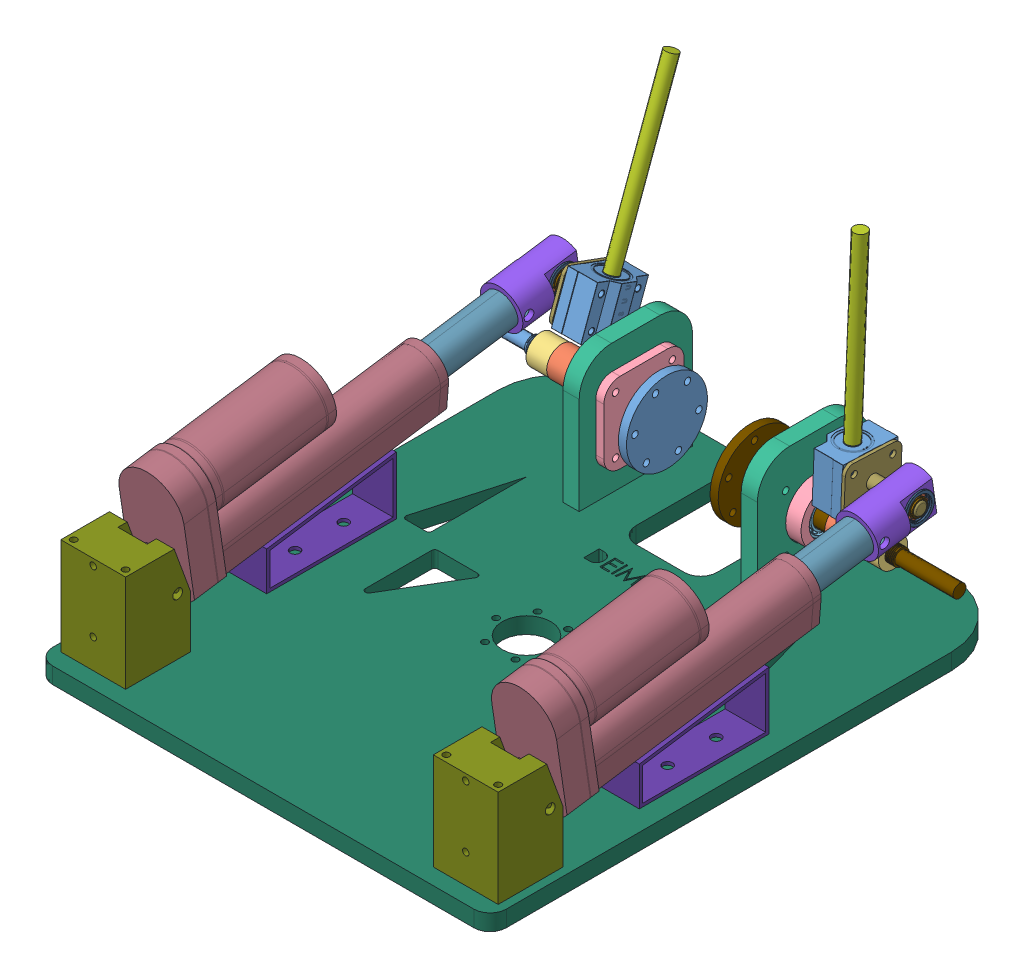
SolidWorks assembly Arm_base_2025_Final, configuration Default. Lengths in mm.
Overall size (299.6 226.1 337.68).
87 component instances, 19 part files, 69 mates.
Components (placement in the parent):
- V8_shaftURC 2024_V4-1: V8_shaftURC 2024_V4 [Default] at (197.7714 146.5943 146.238) x (1 0 0) z (0 -0.634045 -0.773296) size (119 50 50)
- linnear rod coupler-1: linnear rod coupler [Default] at (207.7714 137.6403 153.5796) x (0 -0.344758 -0.938692) z (-1 0 0) size (18.5 18.5 20.01)
- lock_nut_for coupler-1: lock_nut_for coupler [Default] at (187.7714 137.6403 153.5796) x (0 0.998189 -0.060159) z (-1 0 0) size (18 18 13)
- base bearing assambly-1: base bearing assambly [Default] at (252.6957 114.573 131.7936) x (0 0 1) z (-1 0 0) size (49.5 49.5 24)
  - base shaft bearing housing-1: base shaft bearing housing [Default] at (21.786 23.0673 38.1242) size (49.5 49.5 24)
  - 61802  15x24x5mm-1: 61802  15x24x5mm [Default] at (21.786 23.0673 36.1242) x (0 0 -1) z (1 0 0) size (5 24 24)
  - 61802  15x24x5mm-2: 61802  15x24x5mm [Default] at (21.786 23.0673 21.1242) x (0 0 -1) z (1 0 0) size (5 24 24)
- V8_bearing holder holderURC 2024_V4-1: V8_bearing holder holderURC 2024_V4 [Default] at (233.5714 177.6403 118.5796) x (0 0 1) z (-1 0 0) size (70 110 10)
- linear guid rod-1: linear guid rod [Default] at (201.7714 143.2724 151.511) x (0.999217 0.013638 0.037132) z (-0.039557 0.344488 0.937957) size (8 150 8)
- Connector to Linear bearing-1: Connector to Linear bearing [Default] at (150.0852 181.1033 174.7312) x (1 0 0) z (0 0.146923 -0.989148) size (26 26 42.97)
  - V8_connectorURC 2024_V4-1: V8_connectorURC 2024_V4 [Default] at (18.4863 3.099 40.9035) size (26 26 40)
  - V8_F688ZZ_assemblyURC 2024_V4-1: V8_F688ZZ_assemblyURC 2024_V4 [Default] at (27.6778 16.099 30.9035) x (0 1 0) z (0 0 1) size (20.89 5 20.89)
    - V8_F688ZZ_shaftURC 2024_V4-1: V8_F688ZZ_shaftURC 2024_V4 [Default] at origin size (10.7 5 10.7)
    - V8_F688ZZ_HousingURC 2024_V4-1: V8_F688ZZ_HousingURC 2024_V4 [Default] x (0.984312 0 0.176438) z (-0.176438 0 0.984312) size (18 5 18)
    - V8_F688ZZ_BallURC 2024_V4-1: V8_F688ZZ_BallURC 2024_V4 [Default] at (5.5752 2.5 -2.1489) x (0.959238 0.232099 0.161224) z (-0.142462 -0.095558 0.985177) size (2 2 2)
    - V8_F688ZZ_BallURC 2024_V4-20: V8_F688ZZ_BallURC 2024_V4 [Default] at (3.2474 2.5 -5.0155) x (0.870805 0.232099 -0.433393) z (0.463818 -0.095558 0.880762) size (2 2 2)
    - V8_F688ZZ_BallURC 2024_V4-21: V8_F688ZZ_BallURC 2024_V4 [Default] at (-0.3209 2.5 -5.9664) x (0.449753 0.232099 -0.862469) z (0.892936 -0.095558 0.439926) size (2 2 2)
    - V8_F688ZZ_BallURC 2024_V4-22: V8_F688ZZ_BallURC 2024_V4 [Default] at (-3.7665 2.5 -4.6383) x (-0.143088 0.232099 -0.96211) z (0.980982 -0.095558 -0.168947) size (2 2 2)
    - V8_F688ZZ_BallURC 2024_V4-23: V8_F688ZZ_BallURC 2024_V4 [Default] at (-5.7735 2.5 -1.5385) x (-0.681275 0.232099 -0.694258) z (0.694326 -0.095558 -0.713288) size (2 2 2)
    - V8_F688ZZ_BallURC 2024_V4-24: V8_F688ZZ_BallURC 2024_V4 [Default] at (-5.5752 2.5 2.1489) x (-0.959238 0.232099 -0.161224) z (0.142462 -0.095558 -0.985177) size (2 2 2)
    - V8_F688ZZ_BallURC 2024_V4-25: V8_F688ZZ_BallURC 2024_V4 [Default] at (-3.2474 2.5 5.0155) x (-0.870805 0.232099 0.433393) z (-0.463818 -0.095558 -0.880762) size (2 2 2)
    - V8_F688ZZ_BallURC 2024_V4-26: V8_F688ZZ_BallURC 2024_V4 [Default] at (0.3209 2.5 5.9664) x (-0.449753 0.232099 0.862469) z (-0.892936 -0.095558 -0.439926) size (2 2 2)
    - V8_F688ZZ_BallURC 2024_V4-27: V8_F688ZZ_BallURC 2024_V4 [Default] at (3.7665 2.5 4.6383) x (0.143088 0.232099 0.96211) z (-0.980982 -0.095558 0.168947) size (2 2 2)
    - V8_F688ZZ_BallURC 2024_V4-28: V8_F688ZZ_BallURC 2024_V4 [Default] at (5.7735 2.5 1.5385) x (0.681275 0.232099 0.694258) z (-0.694326 -0.095558 0.713288) size (2 2 2)
  - V8_F688ZZ_assemblyURC 2024_V4-2: V8_F688ZZ_assemblyURC 2024_V4 [Default] at (9.2948 16.099 30.9035) x (0 -0.381849 0.924225) z (0 0.924225 0.381849) size (20.89 5 20.89)
    - V8_F688ZZ_shaftURC 2024_V4-1: V8_F688ZZ_shaftURC 2024_V4 [Default] at origin size (10.7 5 10.7)
    - V8_F688ZZ_HousingURC 2024_V4-1: V8_F688ZZ_HousingURC 2024_V4 [Default] x (0.984312 0 0.176438) z (-0.176438 0 0.984312) size (18 5 18)
    - V8_F688ZZ_BallURC 2024_V4-1: V8_F688ZZ_BallURC 2024_V4 [Default] at (5.5752 2.5 -2.1489) x (0.959238 0.232099 0.161224) z (-0.142462 -0.095558 0.985177) size (2 2 2)
    - V8_F688ZZ_BallURC 2024_V4-20: V8_F688ZZ_BallURC 2024_V4 [Default] at (3.2474 2.5 -5.0155) x (0.870805 0.232099 -0.433393) z (0.463818 -0.095558 0.880762) size (2 2 2)
    - V8_F688ZZ_BallURC 2024_V4-21: V8_F688ZZ_BallURC 2024_V4 [Default] at (-0.3209 2.5 -5.9664) x (0.449753 0.232099 -0.862469) z (0.892936 -0.095558 0.439926) size (2 2 2)
    - V8_F688ZZ_BallURC 2024_V4-22: V8_F688ZZ_BallURC 2024_V4 [Default] at (-3.7665 2.5 -4.6383) x (-0.143088 0.232099 -0.96211) z (0.980982 -0.095558 -0.168947) size (2 2 2)
    - V8_F688ZZ_BallURC 2024_V4-23: V8_F688ZZ_BallURC 2024_V4 [Default] at (-5.7735 2.5 -1.5385) x (-0.681275 0.232099 -0.694258) z (0.694326 -0.095558 -0.713288) size (2 2 2)
    - V8_F688ZZ_BallURC 2024_V4-24: V8_F688ZZ_BallURC 2024_V4 [Default] at (-5.5752 2.5 2.1489) x (-0.959238 0.232099 -0.161224) z (0.142462 -0.095558 -0.985177) size (2 2 2)
    - V8_F688ZZ_BallURC 2024_V4-25: V8_F688ZZ_BallURC 2024_V4 [Default] at (-3.2474 2.5 5.0155) x (-0.870805 0.232099 0.433393) z (-0.463818 -0.095558 -0.880762) size (2 2 2)
    - V8_F688ZZ_BallURC 2024_V4-26: V8_F688ZZ_BallURC 2024_V4 [Default] at (0.3209 2.5 5.9664) x (-0.449753 0.232099 0.862469) z (-0.892936 -0.095558 -0.439926) size (2 2 2)
    - V8_F688ZZ_BallURC 2024_V4-27: V8_F688ZZ_BallURC 2024_V4 [Default] at (3.7665 2.5 4.6383) x (0.143088 0.232099 0.96211) z (-0.980982 -0.095558 0.168947) size (2 2 2)
    - V8_F688ZZ_BallURC 2024_V4-28: V8_F688ZZ_BallURC 2024_V4 [Default] at (5.7735 2.5 1.5385) x (0.681275 0.232099 0.694258) z (-0.694326 -0.095558 0.713288) size (2 2 2)
- V8_bearing and cam connection_for_v4URC 2024_V4-1: V8_bearing and cam connection_for_v4URC 2024_V4 [Default] at (188.5714 161.6723 163.3962) x (0 0.938692 -0.344758) z (1 0 0) size (30 35 32)
- V8_LA_Body_V4-1: V8_LA_Body_V4 [Default] at (168.5714 140.8866 383.557) x (0 -0.989148 -0.146923) z (-1 0 0) size (74 184 40)
- V8_LA_RodURC 2024_V4-1: V8_LA_RodURC 2024_V4 [Default] at (168.5714 166.9279 160.5915) x (1 0 0) z (0 -0.989148 -0.146923) size (20 121 20)
- V8_base plate for LAURC 2024_V4-1: V8_base plate for LAURC 2024_V4 [Default] at (283.5714 87.6403 412.2334) x (0 0 -1) z (0 1 0) size (325 280 10)
- LA_back holder-1: LA_back holder [Default] at (168.5714 157.6403 403.5796) x (-1 0 0) z (0 0 -1) size (40 60 40)
- LA_triangular holder_30mm-1: LA_triangular holder_30mm [Default] at (181.0714 97.6403 248.9692) x (0 0 1) z (-1 0 0) size (80 35.85 25)
- Connector to Linear bearing-2: Connector to Linear bearing [Default] at (380.0852 179.5504 185.186) x (1 0 0) z (0 0.146923 -0.989148) size (26 26 42.97)
  - V8_connectorURC 2024_V4-1: V8_connectorURC 2024_V4 [Default] at (18.4863 3.099 40.9035) size (26 26 40)
  - V8_F688ZZ_assemblyURC 2024_V4-1: V8_F688ZZ_assemblyURC 2024_V4 [Default] at (27.6778 16.099 30.9035) x (0 1 0) z (0 0 1) size (20.89 5 20.89)
    - V8_F688ZZ_shaftURC 2024_V4-1: V8_F688ZZ_shaftURC 2024_V4 [Default] at origin size (10.7 5 10.7)
    - V8_F688ZZ_HousingURC 2024_V4-1: V8_F688ZZ_HousingURC 2024_V4 [Default] x (0.984312 0 0.176438) z (-0.176438 0 0.984312) size (18 5 18)
    - V8_F688ZZ_BallURC 2024_V4-1: V8_F688ZZ_BallURC 2024_V4 [Default] at (5.5752 2.5 -2.1489) x (0.959238 0.232099 0.161224) z (-0.142462 -0.095558 0.985177) size (2 2 2)
    - V8_F688ZZ_BallURC 2024_V4-20: V8_F688ZZ_BallURC 2024_V4 [Default] at (3.2474 2.5 -5.0155) x (0.870805 0.232099 -0.433393) z (0.463818 -0.095558 0.880762) size (2 2 2)
    - V8_F688ZZ_BallURC 2024_V4-21: V8_F688ZZ_BallURC 2024_V4 [Default] at (-0.3209 2.5 -5.9664) x (0.449753 0.232099 -0.862469) z (0.892936 -0.095558 0.439926) size (2 2 2)
    - V8_F688ZZ_BallURC 2024_V4-22: V8_F688ZZ_BallURC 2024_V4 [Default] at (-3.7665 2.5 -4.6383) x (-0.143088 0.232099 -0.96211) z (0.980982 -0.095558 -0.168947) size (2 2 2)
    - V8_F688ZZ_BallURC 2024_V4-23: V8_F688ZZ_BallURC 2024_V4 [Default] at (-5.7735 2.5 -1.5385) x (-0.681275 0.232099 -0.694258) z (0.694326 -0.095558 -0.713288) size (2 2 2)
    - V8_F688ZZ_BallURC 2024_V4-24: V8_F688ZZ_BallURC 2024_V4 [Default] at (-5.5752 2.5 2.1489) x (-0.959238 0.232099 -0.161224) z (0.142462 -0.095558 -0.985177) size (2 2 2)
    - V8_F688ZZ_BallURC 2024_V4-25: V8_F688ZZ_BallURC 2024_V4 [Default] at (-3.2474 2.5 5.0155) x (-0.870805 0.232099 0.433393) z (-0.463818 -0.095558 -0.880762) size (2 2 2)
    - V8_F688ZZ_BallURC 2024_V4-26: V8_F688ZZ_BallURC 2024_V4 [Default] at (0.3209 2.5 5.9664) x (-0.449753 0.232099 0.862469) z (-0.892936 -0.095558 -0.439926) size (2 2 2)
    - V8_F688ZZ_BallURC 2024_V4-27: V8_F688ZZ_BallURC 2024_V4 [Default] at (3.7665 2.5 4.6383) x (0.143088 0.232099 0.96211) z (-0.980982 -0.095558 0.168947) size (2 2 2)
    - V8_F688ZZ_BallURC 2024_V4-28: V8_F688ZZ_BallURC 2024_V4 [Default] at (5.7735 2.5 1.5385) x (0.681275 0.232099 0.694258) z (-0.694326 -0.095558 0.713288) size (2 2 2)
  - V8_F688ZZ_assemblyURC 2024_V4-2: V8_F688ZZ_assemblyURC 2024_V4 [Default] at (9.2948 16.099 30.9035) x (0 -0.381849 0.924225) z (0 0.924225 0.381849) size (20.89 5 20.89)
    - V8_F688ZZ_shaftURC 2024_V4-1: V8_F688ZZ_shaftURC 2024_V4 [Default] at origin size (10.7 5 10.7)
    - V8_F688ZZ_HousingURC 2024_V4-1: V8_F688ZZ_HousingURC 2024_V4 [Default] x (0.984312 0 0.176438) z (-0.176438 0 0.984312) size (18 5 18)
    - V8_F688ZZ_BallURC 2024_V4-1: V8_F688ZZ_BallURC 2024_V4 [Default] at (5.5752 2.5 -2.1489) x (0.959238 0.232099 0.161224) z (-0.142462 -0.095558 0.985177) size (2 2 2)
    - V8_F688ZZ_BallURC 2024_V4-20: V8_F688ZZ_BallURC 2024_V4 [Default] at (3.2474 2.5 -5.0155) x (0.870805 0.232099 -0.433393) z (0.463818 -0.095558 0.880762) size (2 2 2)
    - V8_F688ZZ_BallURC 2024_V4-21: V8_F688ZZ_BallURC 2024_V4 [Default] at (-0.3209 2.5 -5.9664) x (0.449753 0.232099 -0.862469) z (0.892936 -0.095558 0.439926) size (2 2 2)
    - V8_F688ZZ_BallURC 2024_V4-22: V8_F688ZZ_BallURC 2024_V4 [Default] at (-3.7665 2.5 -4.6383) x (-0.143088 0.232099 -0.96211) z (0.980982 -0.095558 -0.168947) size (2 2 2)
    - V8_F688ZZ_BallURC 2024_V4-23: V8_F688ZZ_BallURC 2024_V4 [Default] at (-5.7735 2.5 -1.5385) x (-0.681275 0.232099 -0.694258) z (0.694326 -0.095558 -0.713288) size (2 2 2)
    - V8_F688ZZ_BallURC 2024_V4-24: V8_F688ZZ_BallURC 2024_V4 [Default] at (-5.5752 2.5 2.1489) x (-0.959238 0.232099 -0.161224) z (0.142462 -0.095558 -0.985177) size (2 2 2)
    - V8_F688ZZ_BallURC 2024_V4-25: V8_F688ZZ_BallURC 2024_V4 [Default] at (-3.2474 2.5 5.0155) x (-0.870805 0.232099 0.433393) z (-0.463818 -0.095558 -0.880762) size (2 2 2)
    - V8_F688ZZ_BallURC 2024_V4-26: V8_F688ZZ_BallURC 2024_V4 [Default] at (0.3209 2.5 5.9664) x (-0.449753 0.232099 0.862469) z (-0.892936 -0.095558 -0.439926) size (2 2 2)
    - V8_F688ZZ_BallURC 2024_V4-27: V8_F688ZZ_BallURC 2024_V4 [Default] at (3.7665 2.5 4.6383) x (0.143088 0.232099 0.96211) z (-0.980982 -0.095558 0.168947) size (2 2 2)
    - V8_F688ZZ_BallURC 2024_V4-28: V8_F688ZZ_BallURC 2024_V4 [Default] at (5.7735 2.5 1.5385) x (0.681275 0.232099 0.694258) z (-0.694326 -0.095558 0.713288) size (2 2 2)
- LA_back holder-2: LA_back holder [Default] at (398.5714 157.6403 403.5796) x (-1 0 0) z (0 0 -1) size (40 60 40)
- V8_bearing and cam connection_for_v4URC 2024_V4-2: V8_bearing and cam connection_for_v4URC 2024_V4 [Default] at (378.5714 183.9124 169.0846) x (0 -0.999056 0.04343) z (-1 0 0) size (30 35 32)
- V8_LA_RodURC 2024_V4-2: V8_LA_RodURC 2024_V4 [Default] at (398.5714 165.375 171.0464) x (1 0 0) z (0 -0.989148 -0.146923) size (20 121 20)
- linnear rod coupler-2: linnear rod coupler [Default] at (359.3714 137.6403 153.5796) x (0 0.04343 0.999056) z (1 0 0) size (18.5 18.5 20.01)
- lock_nut_for coupler-2: lock_nut_for coupler [Default] at (379.3714 137.6403 153.5796) x (0 -0.658716 -0.752392) z (1 0 0) size (18 18 13)
- linear guid rod-2: linear guid rod [Default] at (365.3714 143.6346 153.319) x (-0.587704 0.035138 0.808312) z (-0.809076 -0.025524 -0.58715) size (8 150 8)
- base bearing assambly-2: base bearing assambly [Default] at (314.4472 114.573 175.3656) x (0 0 -1) z (1 0 0) size (49.5 49.5 24)
  - base shaft bearing housing-1: base shaft bearing housing [Default] at (21.786 23.0673 38.1242) size (49.5 49.5 24)
  - 61802  15x24x5mm-1: 61802  15x24x5mm [Default] at (21.786 23.0673 36.1242) x (0 0 -1) z (1 0 0) size (5 24 24)
  - 61802  15x24x5mm-2: 61802  15x24x5mm [Default] at (21.786 23.0673 21.1242) x (0 0 -1) z (1 0 0) size (5 24 24)
- base_shaft_link2_V4-1: base_shaft_link2_V4 [Default] at (359.3714 130.6412 162.8038) x (-1 0 0) z (0 -0.796635 -0.604461) size (129 50 50)
- LA_triangular holder_30mm-2: LA_triangular holder_30mm [Default] at (411.0714 97.6403 248.9692) x (0 0 1) z (-1 0 0) size (80 35.85 25)
- V8_bearing holder holderURC 2024_V4-2: V8_bearing holder holderURC 2024_V4 [Default] at (333.5714 177.6403 188.5796) x (0 0 -1) z (1 0 0) size (70 110 10)
- V8_LA_Body_V4-2: V8_LA_Body_V4 [Default] at (398.5714 140.8866 383.557) x (0 -0.989148 -0.146923) z (-1 0 0) size (74 184 40)
- linear bearing robotic arm-1: linear bearing robotic arm [Default] at (199.3393 155.6391 146.9691) x (0 -0.344758 -0.938692) z (1 0 0) size (34 30.1 22.2)
- linear bearing robotic arm-2: linear bearing robotic arm [Default] at (367.8035 183.1523 151.6012) x (0 -0.04343 -0.999056) z (-1 0 0) size (34 30.1 22.2)
Mates (geometry in assembly coordinates):
- Coincident12: coincident anti-aligned: plane of V8_base plate for LAURC 2024_V4-1 through (283.5714 97.6403 412.2334) normal (0 1 0); plane of LA_back holder-1 through (168.5714 97.6403 403.5796) normal (0 -1 0)
- Concentric4: concentric anti-aligned: cylinder of Connector to Linear bearing-1/V8_F688ZZ_assemblyURC 2024_V4-2/V8_F688ZZ_shaftURC 2024_V4-1 through (164.3799 169.7194 141.7977) axis (-1 0 0) radius 4; cylinder of V8_bearing and cam connection_for_v4URC 2024_V4-1 through (158.5714 169.7194 141.7977) axis (1 0 0) radius 4
- Distance6: distance = 20 mm: cylinder of Connector to Linear bearing-1/V8_connectorURC 2024_V4-1 through (168.5714 167.5156 156.635) axis (0 -0.146923 0.989148) radius 13; plane of V8_bearing and cam connection_for_v4URC 2024_V4-1 through (188.5714 161.6723 163.3962) normal (-1 0 0)
- Concentric9: concentric anti-aligned: cylinder of Connector to Linear bearing-1/V8_connectorURC 2024_V4-1 through (168.5714 167.5156 156.635) axis (0 -0.146923 0.989148) radius 10; cylinder of V8_LA_RodURC 2024_V4-1 through (168.5714 149.1502 280.2785) axis (0 0.146923 -0.989148) radius 10
- Concentric10: concentric anti-aligned: cylinder of Connector to Linear bearing-1/V8_connectorURC 2024_V4-1 through (198.5714 165.8994 167.5156) axis (-1 0 0) radius 3; cylinder of V8_LA_RodURC 2024_V4-1 through (158.5704 165.8994 167.5156) axis (1 0 0) radius 3
- Parallel3: parallel anti-aligned: plane of Connector to Linear bearing-1/V8_connectorURC 2024_V4-1 through (176.663 181.1091 153.5992) normal (1 0 0); plane of V8_LA_Body_V4-1 through (148.5714 170.5321 367.7409) normal (-1 0 0)
- Concentric7: concentric aligned: cylinder of V8_LA_Body_V4-1 through (168.5714 132.7454 390.7229) axis (0 0.146923 -0.989148) radius 10; cylinder of V8_LA_RodURC 2024_V4-1 through (168.5714 149.1502 280.2785) axis (0 0.146923 -0.989148) radius 10
- Parallel7: parallel aligned: plane of V8_bearing and cam connection_for_v4URC 2024_V4-1 through (188.5714 161.6723 163.3962) normal (-1 0 0); plane of V8_base plate for LAURC 2024_V4-1 through (143.5714 97.6403 412.2334) normal (-1 0 0)
- Coincident16: coincident anti-aligned: plane of V8_LA_Body_V4-1 through (159.5714 138.242 401.3617) normal (-1 0 0); plane of LA_back holder-1 through (159.5714 107.6403 403.5796) normal (1 0 0)
- Concentric13: concentric aligned: cylinder of V8_LA_Body_V4-1 through (186.0567 132.6403 391.4309) axis (-1 0 0) radius 3; cylinder of LA_back holder-1 through (216.5714 132.6403 391.4309) axis (-1 0 0) radius 3
- Concentric1: concentric aligned: cylinder of V8_shaftURC 2024_V4-1 through (252.7714 137.6403 153.5796) axis (1 0 0) radius 7.5; cylinder of linnear rod coupler-1 through (187.7714 137.6403 153.5796) axis (1 0 0) radius 9.25
- Coincident17: coincident anti-aligned: plane of V8_shaftURC 2024_V4-1 through (207.7714 137.6403 153.5796) normal (-1 0 0); plane of linnear rod coupler-1 through (207.7714 137.6403 153.5796) normal (1 0 0)
- Concentric2: concentric aligned: cylinder of V8_shaftURC 2024_V4-1 through (252.7714 137.6403 153.5796) axis (1 0 0) radius 7.5; cylinder of lock_nut_for coupler-1 through (174.7714 137.6403 153.5796) axis (1 0 0) radius 9
- Concentric3: concentric anti-aligned: cylinder of V8_shaftURC 2024_V4-1 through (252.7714 137.6403 153.5796) axis (1 0 0) radius 7.5; cylinder of base bearing assambly-1/base shaft bearing housing-1 through (214.5714 137.6403 153.5796) axis (-1 0 0) radius 8
- Tangent2: tangent anti-aligned: cylinder of V8_shaftURC 2024_V4-1 through (182.7714 137.6403 153.5796) axis (1 0 0) radius 6; plane of linear guid rod-1 through (201.7714 143.2724 151.511) normal (0 -0.938692 0.344758)
- Concentric14: concentric aligned: cylinder of linnear rod coupler-1 through (201.7714 148.9046 149.4425) axis (0 -0.938692 0.344758) radius 4; cylinder of linear guid rod-1 through (201.7714 284.0762 99.7974) axis (0 -0.938692 0.344758) radius 4
- Concentric15: concentric anti-aligned: cylinder of base bearing assambly-1/base shaft bearing housing-1 through (214.5714 137.6403 153.5796) axis (-1 0 0) radius 17; cylinder of V8_bearing holder holderURC 2024_V4-1 through (223.5714 137.6403 153.5796) axis (1 0 0) radius 17.5
- Concentric16: concentric anti-aligned: cylinder of base bearing assambly-1/base shaft bearing housing-1 through (228.5714 155.1403 171.0796) axis (1 0 0) radius 2; cylinder of V8_bearing holder holderURC 2024_V4-1 through (233.5714 155.1403 171.0796) axis (-1 0 0) radius 2
- Concentric17: concentric anti-aligned: cylinder of base bearing assambly-1/base shaft bearing housing-1 through (228.5714 155.1403 136.0796) axis (1 0 0) radius 2; cylinder of V8_bearing holder holderURC 2024_V4-1 through (233.5714 155.1403 136.0796) axis (-1 0 0) radius 2
- Coincident18: coincident anti-aligned: plane of base bearing assambly-1/base shaft bearing housing-1 through (233.5714 172.6403 153.5796) normal (-1 0 0); plane of V8_bearing holder holderURC 2024_V4-1 through (233.5714 177.6403 118.5796) normal (1 0 0)
- Coincident19: coincident anti-aligned: plane of V8_bearing holder holderURC 2024_V4-1 through (223.5714 97.6403 118.5796) normal (0 -1 0); plane of V8_base plate for LAURC 2024_V4-1 through (283.5714 97.6403 412.2334) normal (0 1 0)
- Coincident20: coincident anti-aligned: plane of V8_bearing holder holderURC 2024_V4-1 through (223.5714 177.6403 128.5796) normal (0 0 -1); plane of V8_base plate for LAURC 2024_V4-1 through (283.5714 97.6403 128.5796) normal (0 0 1)
- Coincident21: coincident anti-aligned: plane of V8_bearing holder holderURC 2024_V4-1 through (233.5714 177.6403 118.5796) normal (1 0 0); plane of V8_base plate for LAURC 2024_V4-1 through (233.5714 97.6403 412.2334) normal (-1 0 0)
- Concentric21: concentric aligned: cylinder of V8_LA_Body_V4-1 through (186.0567 132.6403 391.4309) axis (-1 0 0) radius 3; cylinder of LA_back holder-1 through (216.5714 132.6403 391.4309) axis (-1 0 0) radius 3
- Coincident23: coincident anti-aligned: plane of linnear rod coupler-1 through (187.7714 137.6403 153.5796) normal (-1 0 0); plane of lock_nut_for coupler-1 through (187.7714 137.6403 153.5796) normal (1 0 0)
- Concentric24: concentric anti-aligned: cylinder of V8_base plate for LAURC 2024_V4-1 through (152.5714 87.6403 419.5796) axis (0 1 0) radius 2.5; cylinder of LA_back holder-1 through (152.5714 185.6403 419.5796) axis (0 -1 0) radius 2
- Concentric25: concentric anti-aligned: cylinder of V8_base plate for LAURC 2024_V4-1 through (184.5714 87.6403 419.5796) axis (0 1 0) radius 2.5; cylinder of LA_back holder-1 through (184.5714 185.6403 419.5796) axis (0 -1 0) radius 2
- Coincident24: coincident anti-aligned: plane of V8_base plate for LAURC 2024_V4-1 through (283.5714 97.6403 412.2334) normal (0 1 0); plane of LA_triangular holder_30mm-1 through (156.0714 97.6403 248.9692) normal (0 -1 0)
- Width1: width anti-aligned: plane of V8_LA_Body_V4-1 through (148.5714 170.5321 367.7409) normal (-1 0 0); plane of V8_LA_Body_V4-1 through (188.5714 170.5321 367.7409) normal (1 0 0); plane of LA_triangular holder_30mm-1 through (181.0714 97.6403 248.9692) normal (1 0 0); plane of LA_triangular holder_30mm-1 through (156.0714 97.6403 248.9692) normal (-1 0 0)
- Concentric26: concentric aligned: cylinder of Connector to Linear bearing-2/V8_F688ZZ_assemblyURC 2024_V4-2/V8_F688ZZ_shaftURC 2024_V4-1 through (394.3799 168.1665 152.2526) axis (-1 0 0) radius 4; cylinder of V8_bearing and cam connection_for_v4URC 2024_V4-2 through (408.5714 168.1665 152.2526) axis (-1 0 0) radius 4
- Distance7: distance = 20 mm: cylinder of Connector to Linear bearing-2/V8_connectorURC 2024_V4-1 through (398.5714 165.9627 167.0898) axis (0 -0.146923 0.989148) radius 13; plane of V8_bearing and cam connection_for_v4URC 2024_V4-2 through (378.5714 183.9124 169.0846) normal (1 0 0)
- Concentric27: concentric anti-aligned: cylinder of Connector to Linear bearing-2/V8_connectorURC 2024_V4-1 through (398.5714 165.9627 167.0898) axis (0 -0.146923 0.989148) radius 10; cylinder of V8_LA_RodURC 2024_V4-2 through (398.5714 147.5973 290.7333) axis (0 0.146923 -0.989148) radius 10
- Parallel12: parallel anti-aligned: plane of Connector to Linear bearing-2/V8_connectorURC 2024_V4-1 through (406.663 179.5562 164.0541) normal (1 0 0); plane of V8_LA_Body_V4-2 through (378.5714 170.5321 367.7409) normal (-1 0 0)
- Concentric31: concentric aligned: cylinder of V8_LA_RodURC 2024_V4-2 through (398.5714 147.5973 290.7333) axis (0 0.146923 -0.989148) radius 10; cylinder of V8_LA_Body_V4-2 through (398.5714 132.7454 390.7229) axis (0 0.146923 -0.989148) radius 10
- Concentric33: concentric aligned: cylinder of linnear rod coupler-2 through (379.3714 137.6403 153.5796) axis (-1 0 0) radius 9.25; cylinder of base_shaft_link2_V4-1 through (304.3714 137.6403 153.5796) axis (-1 0 0) radius 7.5
- Coincident28: coincident anti-aligned: plane of linnear rod coupler-2 through (359.3714 137.6403 153.5796) normal (-1 0 0); plane of base_shaft_link2_V4-1 through (359.3714 137.6403 153.5796) normal (1 0 0)
- Concentric34: concentric aligned: cylinder of lock_nut_for coupler-2 through (392.3714 137.6403 153.5796) axis (-1 0 0) radius 9; cylinder of base_shaft_link2_V4-1 through (304.3714 137.6403 153.5796) axis (-1 0 0) radius 7.5
- Concentric35: concentric anti-aligned: cylinder of base bearing assambly-2/base shaft bearing housing-1 through (352.5714 137.6403 153.5796) axis (1 0 0) radius 8; cylinder of base_shaft_link2_V4-1 through (304.3714 137.6403 153.5796) axis (-1 0 0) radius 7.5
- Tangent6: tangent anti-aligned: plane of linear guid rod-2 through (365.3714 143.6346 153.319) normal (0 -0.999056 0.04343); cylinder of base_shaft_link2_V4-1 through (384.3714 137.6403 153.5796) axis (-1 0 0) radius 6
- Concentric36: concentric aligned: cylinder of linnear rod coupler-2 through (365.3714 149.6289 153.0584) axis (0 -0.999056 0.04343) radius 4; cylinder of linear guid rod-2 through (365.3714 293.4931 146.8046) axis (0 -0.999056 0.04343) radius 4
- Concentric37: concentric anti-aligned: cylinder of base bearing assambly-2/base shaft bearing housing-1 through (352.5714 137.6403 153.5796) axis (1 0 0) radius 17; cylinder of V8_bearing holder holderURC 2024_V4-2 through (343.5714 137.6403 153.5796) axis (-1 0 0) radius 17.5
- Concentric38: concentric anti-aligned: cylinder of base bearing assambly-2/base shaft bearing housing-1 through (338.5714 155.1403 136.0796) axis (-1 0 0) radius 2; cylinder of V8_bearing holder holderURC 2024_V4-2 through (333.5714 155.1403 136.0796) axis (1 0 0) radius 2
- Concentric39: concentric anti-aligned: cylinder of base bearing assambly-2/base shaft bearing housing-1 through (338.5714 155.1403 171.0796) axis (-1 0 0) radius 2; cylinder of V8_bearing holder holderURC 2024_V4-2 through (333.5714 155.1403 171.0796) axis (1 0 0) radius 2
- Coincident29: coincident anti-aligned: plane of base bearing assambly-2/base shaft bearing housing-1 through (333.5714 172.6403 153.5796) normal (1 0 0); plane of V8_bearing holder holderURC 2024_V4-2 through (333.5714 177.6403 188.5796) normal (-1 0 0)
- Coincident30: coincident anti-aligned: plane of linnear rod coupler-2 through (379.3714 137.6403 153.5796) normal (1 0 0); plane of lock_nut_for coupler-2 through (379.3714 137.6403 153.5796) normal (-1 0 0)
- Width2: width anti-aligned: plane of V8_LA_Body_V4-2 through (378.5714 170.5321 367.7409) normal (-1 0 0); plane of V8_LA_Body_V4-2 through (418.5714 170.5321 367.7409) normal (1 0 0); plane of LA_triangular holder_30mm-2 through (411.0714 97.6403 248.9692) normal (1 0 0); plane of LA_triangular holder_30mm-2 through (386.0714 97.6403 248.9692) normal (-1 0 0)
- Coincident31: coincident anti-aligned: plane of V8_base plate for LAURC 2024_V4-1 through (283.5714 97.6403 412.2334) normal (0 1 0); plane of LA_back holder-2 through (398.5714 97.6403 403.5796) normal (0 -1 0)
- Parallel13: parallel aligned: plane of V8_base plate for LAURC 2024_V4-1 through (423.5714 97.6403 412.2334) normal (1 0 0); plane of V8_bearing and cam connection_for_v4URC 2024_V4-2 through (378.5714 183.9124 169.0846) normal (1 0 0)
- Coincident32: coincident anti-aligned: plane of V8_base plate for LAURC 2024_V4-1 through (283.5714 97.6403 412.2334) normal (0 1 0); plane of V8_bearing holder holderURC 2024_V4-2 through (343.5714 97.6403 188.5796) normal (0 -1 0)
- Concentric42: concentric anti-aligned: cylinder of V8_base plate for LAURC 2024_V4-1 through (382.5714 87.6403 419.5796) axis (0 1 0) radius 2.5; cylinder of LA_back holder-2 through (382.5714 185.6403 419.5796) axis (0 -1 0) radius 2
- Concentric43: concentric anti-aligned: cylinder of V8_base plate for LAURC 2024_V4-1 through (414.5714 87.6403 419.5796) axis (0 1 0) radius 2.5; cylinder of LA_back holder-2 through (414.5714 185.6403 419.5796) axis (0 -1 0) radius 2
- Coincident35: coincident anti-aligned: plane of V8_base plate for LAURC 2024_V4-1 through (283.5714 97.6403 412.2334) normal (0 1 0); plane of LA_triangular holder_30mm-2 through (386.0714 97.6403 248.9692) normal (0 -1 0)
- Coincident41: coincident anti-aligned: plane of LA_back holder-2 through (407.5714 107.6403 403.5796) normal (-1 0 0); plane of V8_LA_Body_V4-2 through (407.5714 138.242 401.3617) normal (1 0 0)
- Concentric60: concentric aligned: cylinder of LA_back holder-2 through (446.5714 132.6403 391.4309) axis (-1 0 0) radius 3; cylinder of V8_LA_Body_V4-2 through (416.0567 132.6403 391.4309) axis (-1 0 0) radius 3
- Coincident42: coincident anti-aligned: plane of V8_base plate for LAURC 2024_V4-1 through (343.5714 97.6403 412.2334) normal (-1 0 0); plane of V8_bearing holder holderURC 2024_V4-2 through (343.5714 177.6403 188.5796) normal (1 0 0)
- Coincident43: coincident anti-aligned: plane of V8_base plate for LAURC 2024_V4-1 through (283.5714 97.6403 128.5796) normal (0 0 1); plane of V8_bearing holder holderURC 2024_V4-2 through (343.5714 177.6403 128.5796) normal (0 0 -1)
- Concentric62: concentric anti-aligned: cylinder of Connector to Linear bearing-2/V8_connectorURC 2024_V4-1 through (428.5714 164.3465 177.9704) axis (-1 0 0) radius 3; cylinder of V8_LA_RodURC 2024_V4-2 through (388.5704 164.3465 177.9704) axis (1 0 0) radius 3
- Distance12: distance = 30 mm: cylinder of V8_shaftURC 2024_V4-2 through (304.3714 137.6403 153.5796) axis (-1 0 0) radius 7.5; cylinder of V8_LA_RodURC 2024_V4-2 through (398.5714 147.5973 290.7333) axis (0 0.146923 -0.989148) radius 10
- Coincident44: coincident aligned: plane of LA_triangular holder_30mm-1 through (156.0714 133.4935 248.9692) normal (0 0 -1); plane of LA_triangular holder_30mm-2 through (386.0714 133.4935 248.9692) normal (0 0 -1)
- Coincident46: coincident anti-aligned: plane of V8_bearing and cam connection_for_v4URC 2024_V4-2 through (376.5714 183.9124 169.0846) normal (-1 0 0); plane of linear bearing robotic arm-2 through (376.5714 193.5444 151.1494) normal (1 0 0)
- Concentric65: concentric anti-aligned: cylinder of V8_bearing and cam connection_for_v4URC 2024_V4-2 through (386.5714 159.6962 164.6321) axis (-1 0 0) radius 2; cylinder of linear bearing robotic arm-2 through (368.5714 159.6962 164.6321) axis (1 0 0) radius 1.7
- Concentric66: concentric anti-aligned: cylinder of V8_bearing and cam connection_for_v4URC 2024_V4-2 through (386.5714 177.6792 163.8504) axis (-1 0 0) radius 2; cylinder of linear bearing robotic arm-2 through (368.5714 177.6792 163.8504) axis (1 0 0) radius 1.7
- Coincident47: coincident anti-aligned: plane of V8_bearing and cam connection_for_v4URC 2024_V4-1 through (190.5714 161.6723 163.3962) normal (1 0 0); plane of linear bearing robotic arm-1 through (190.5714 145.8749 150.5552) normal (-1 0 0)
- Concentric67: concentric aligned: cylinder of V8_bearing and cam connection_for_v4URC 2024_V4-1 through (180.5714 174.0305 127.4306) axis (1 0 0) radius 2; cone of linear bearing robotic arm-1 through (190.6714 174.0305 127.4306) axis (1 0 0)
- Concentric68: concentric aligned: cylinder of V8_bearing and cam connection_for_v4URC 2024_V4-1 through (180.5714 157.1341 133.6363) axis (1 0 0) radius 2; cone of linear bearing robotic arm-1 through (190.6714 157.1341 133.6363) axis (1 0 0)
- Concentric69: concentric anti-aligned: cylinder of linear guid rod-2 through (365.3714 293.4931 146.8046) axis (0 -0.999056 0.04343) radius 4; cylinder of linear bearing robotic arm-2 through (365.3714 153.1806 152.904) axis (0 0.999056 -0.04343) radius 4
- Concentric70: concentric aligned: cylinder of linear guid rod-1 through (201.7714 284.0762 99.7974) axis (0 -0.938692 0.344758) radius 4; cylinder of linear bearing robotic arm-1 through (201.7714 183.7998 136.6263) axis (0 -0.938692 0.344758) radius 4
- Concentric71: concentric aligned: cylinder of linnear rod coupler-2 through (379.3714 137.6403 153.5796) axis (-1 0 0) radius 9.25; cylinder of base_shaft_link2_V4-1 through (433.3714 137.6403 153.5796) axis (-1 0 0) radius 4
- Concentric72: concentric aligned: cylinder of V8_shaftURC 2024_V4-1 through (133.7714 137.6403 153.5796) axis (1 0 0) radius 4; cylinder of linnear rod coupler-1 through (187.7714 137.6403 153.5796) axis (1 0 0) radius 9.25
